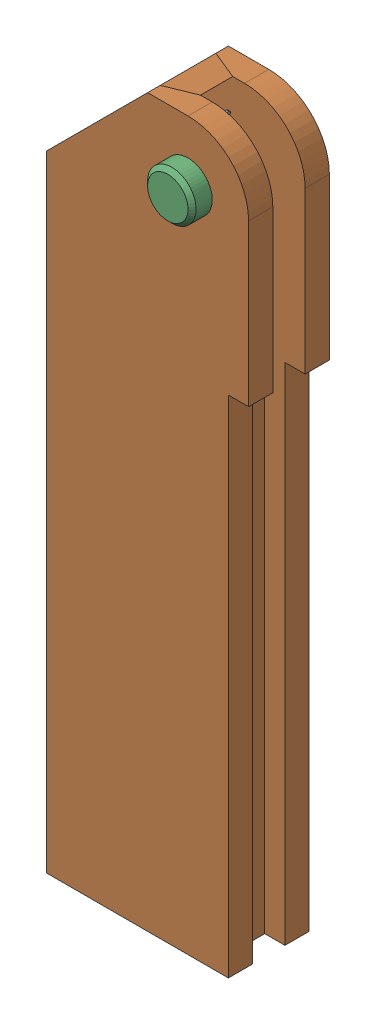
SolidWorks assembly AP_Poulie_Support, configuration Défaut. Lengths in mm.
Overall size (50 179.85 32).
3 component instances, 3 part files, 4 mates.
Components (placement in the parent):
- Poulie_Support-1: Poulie_Support [Défaut] at (-14.684 -4.5338 0) size (50 179.85 20)
- Poulie_Axe-1: Poulie_Axe [Défaut] at (-14.684 -4.5338 10) x (0 0 -1) z (0 1 0) size (32 12 12)
- ring_3am1-6-1: ring_3am1-6 [Default] at (-14.684 -4.5338 -11.6) x (-0.707285 -0.706928 0) z (0 0 1) size (6.95 7.81 0.4)
Mates (geometry in assembly coordinates):
- Coaxiale1: concentric anti-aligned: cylinder of Poulie_Support-1 through (-14.684 -4.5338 10) axis (0 0 -1) radius 3; cylinder of Poulie_Axe-1 through (-14.684 -4.5338 37.0939) axis (0 0 1) radius 3
- Coïncidente1: coincident anti-aligned: plane of Poulie_Support-1 through (-14.684 -4.5338 10) normal (0 0 1); plane of Poulie_Axe-1 through (-17.684 -4.5338 10) normal (0 0 -1)
- Coaxiale2: concentric: cylinder of Poulie_Axe-1 through (-14.684 -4.5338 37.0939) axis (0 0 1) radius 3; cylinder of ring_3am1-6-1 through (-14.684 -4.5338 -11.4) axis (0 0 -1) radius 2.85
- Coïncidente3: coincident: plane of Poulie_Axe-1 through (-17.684 -4.5338 -11.8) normal (0 0 1); moEndPointRef_w of ring_3am1-6-1
